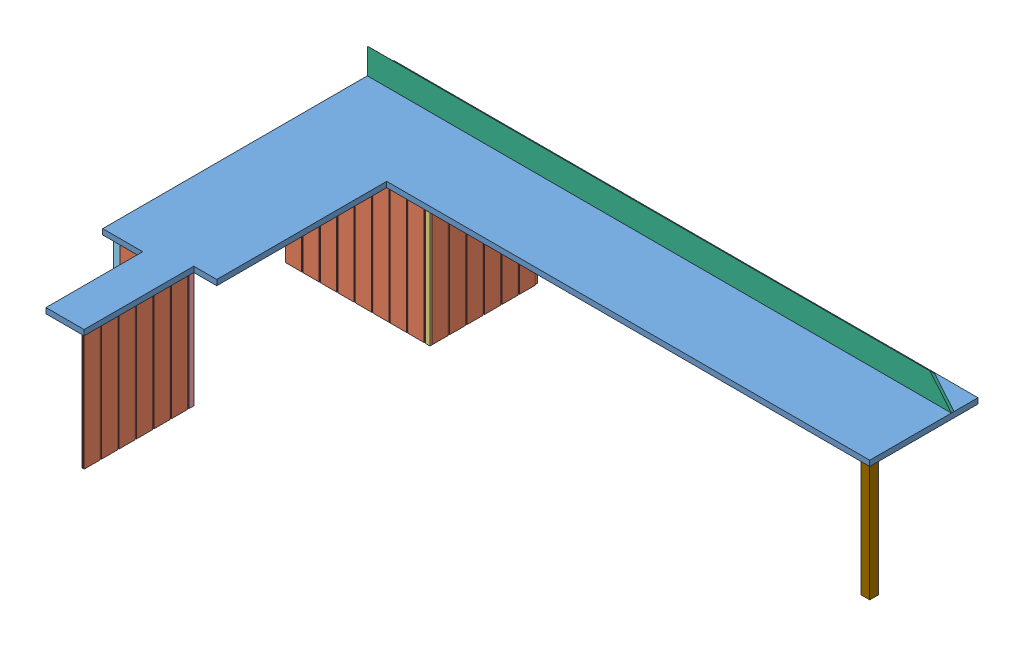
SolidWorks assembly Brüstung-Arbeit, configuration Standard. Lengths in mm.
Overall size (4046.49 1016.32 2687.4).
32 component instances, 9 part files, 94 mates.
Components (placement in the parent):
- Werkplatte-1: Werkplatte [Standard] at (-2563.2532 392.3163 2702.7833) size (4046.49 38 2687.4)
- Schalbrett-1: Schalbrett [Standard] at (-2381.7532 392.3163 3445.7833) x (1 0 0) z (0 0 -1) size (131 800 14)
- Schalbrett-2: Schalbrett [Standard] at (-2260.7532 392.3163 3445.7833) x (1 0 0) z (0 0 -1) size (131 800 14)
- Schalbrett-3: Schalbrett [Standard] at (-2139.7532 392.3163 3445.7833) x (1 0 0) z (0 0 -1) size (131 800 14)
- Schalbrett-4: Schalbrett [Standard] at (-2018.7532 392.3163 3445.7833) x (1 0 0) z (0 0 -1) size (131 800 14)
- Schalbrett-5: Schalbrett [Standard] at (-1897.7532 392.3163 3445.7833) x (1 0 0) z (0 0 -1) size (131 800 14)
- Schalbrett-6: Schalbrett [Standard] at (-1776.7532 392.3163 3445.7833) x (1 0 0) z (0 0 -1) size (131 800 14)
- Schalbrett-7: Schalbrett [Standard] at (-1655.7532 392.3163 3445.7833) x (1 0 0) z (0 0 -1) size (131 800 14)
- Schalbrett-15: Schalbrett [Standard] at (-2502.7532 392.3163 3445.7833) x (1 0 0) z (0 0 -1) size (131 800 14)
- Schalbrett-Ecke1-1: Schalbrett-Ecke1 [Standard] at (-1534.7532 392.3163 3445.7833) x (1 0 0) z (0 0 -1) size (32 800 14)
- Schalbrett-9: Schalbrett [Standard] at (-1570.2532 392.3163 3378.2833) x (0 0 -1) z (-1 0 0) size (131 800 14)
- Schalbrett-10: Schalbrett [Standard] at (-1570.2532 392.3163 3257.2833) x (0 0 -1) z (-1 0 0) size (131 800 14)
- Schalbrett-11: Schalbrett [Standard] at (-1570.2532 392.3163 3136.2833) x (0 0 -1) z (-1 0 0) size (131 800 14)
- Schalbrett-12: Schalbrett [Standard] at (-1570.2532 392.3163 3015.2833) x (0 0 -1) z (-1 0 0) size (131 800 14)
- Schalbrett-13: Schalbrett [Standard] at (-1570.2532 392.3163 2894.2833) x (0 0 -1) z (-1 0 0) size (131 800 14)
- Schalbrett-14: Schalbrett [Standard] at (-1570.2532 392.3163 2773.2833) x (0 0 -1) z (-1 0 0) size (131 800 14)
- Schalbrett-16: Schalbrett [Standard] at (-2029.2532 392.3163 5329.6883) x (0 0 -1) z (-1 0 0) size (131 800 14)
- Schalbrett-17: Schalbrett [Standard] at (-2029.2532 392.3163 5208.6883) x (0 0 -1) z (-1 0 0) size (131 800 14)
- Schalbrett-18: Schalbrett [Standard] at (-2029.2532 392.3163 5087.6883) x (0 0 -1) z (-1 0 0) size (131 800 14)
- Schalbrett-19: Schalbrett [Standard] at (-2029.2532 392.3163 4966.6883) x (0 0 -1) z (-1 0 0) size (131 800 14)
- Schalbrett-20: Schalbrett [Standard] at (-2029.2532 392.3163 4845.6883) x (0 0 -1) z (-1 0 0) size (131 800 14)
- Schalbrett-21: Schalbrett [Standard] at (-2029.2532 392.3163 4724.6883) x (0 0 -1) z (-1 0 0) size (131 800 14)
- Schalbrett-23: Schalbrett [Standard] at (-2096.7532 392.3163 4637.1883) x (-1 0 0) z (0 0 1) size (131 800 14)
- Schalbrett-24: Schalbrett [Standard] at (-2217.7532 392.3163 4637.1883) x (-1 0 0) z (0 0 1) size (131 800 14)
- Schalbrett-25: Schalbrett [Standard] at (-2338.7532 392.3163 4637.1883) x (-1 0 0) z (0 0 1) size (131 800 14)
- Schalbrett-26: Schalbrett [Standard] at (-2459.7532 392.3163 4637.1883) x (-1 0 0) z (0 0 1) size (131 800 14)
- Schalbrett-Ecke2-1: Schalbrett-Ecke2 [Standard] at (-2029.2532 392.3163 4603.6883) x (0 0 -1) z (-1 0 0) size (34 800 14)
- Schalbrett-Ecke3-1: Schalbrett-Ecke3 [Standard] at (-2580.7532 392.3163 4637.1883) x (-1 0 0) z (0 0 1) size (43 800 14)
- Steckdosenleiste-1: Steckdosenleiste [Standard] at (-540.0103 519.4748 2868.9113) size (4046.49 178.32 18)
- Tunnel-Unten-1: Tunnel-Unten [Standard] at (-2488.2532 242.3163 4041.4883) x (0 0 -1) z (1 0 0) size (1177.4 18 150)
- Tunnel-Vorn-1: Tunnel-Vorn [Standard] at (-2431.2532 326.3163 4041.4883) x (0 0 -1) z (1 0 0) size (1177.4 132 18)
- Bein-1: Bein [Standard] at (1453.2326 -407.6837 3422.7833) size (60 800 60)
Mates (geometry in assembly coordinates):
- Deckungsgleich1: coincident anti-aligned: plane of Werkplatte-1 through (-2563.2532 392.3163 2702.7833) normal (0 -1 0); plane of Schalbrett-15 through (-2453.2532 392.3163 3448.7833) normal (0 1 0)
- Deckungsgleich2: coincident anti-aligned: plane of Werkplatte-1 through (-2563.2532 392.3163 2702.7833) normal (0 -1 0); plane of Schalbrett-1 through (-2332.2532 392.3163 3448.7833) normal (0 1 0)
- Deckungsgleich3: coincident anti-aligned: plane of Werkplatte-1 through (-2563.2532 392.3163 2702.7833) normal (0 -1 0); plane of Schalbrett-2 through (-2211.2532 392.3163 3448.7833) normal (0 1 0)
- Deckungsgleich4: coincident anti-aligned: plane of Werkplatte-1 through (-2563.2532 392.3163 2702.7833) normal (0 -1 0); plane of Schalbrett-3 through (-2090.2532 392.3163 3448.7833) normal (0 1 0)
- Deckungsgleich5: coincident anti-aligned: plane of Werkplatte-1 through (-2563.2532 392.3163 2702.7833) normal (0 -1 0); plane of Schalbrett-4 through (-1969.2532 392.3163 3448.7833) normal (0 1 0)
- Deckungsgleich6: coincident anti-aligned: plane of Werkplatte-1 through (-2563.2532 392.3163 2702.7833) normal (0 -1 0); plane of Schalbrett-5 through (-1848.2532 392.3163 3448.7833) normal (0 1 0)
- Deckungsgleich7: coincident anti-aligned: plane of Werkplatte-1 through (-2563.2532 392.3163 2702.7833) normal (0 -1 0); plane of Schalbrett-6 through (-1727.2532 392.3163 3448.7833) normal (0 1 0)
- Deckungsgleich8: coincident anti-aligned: plane of Werkplatte-1 through (-2563.2532 392.3163 2702.7833) normal (0 -1 0); plane of Schalbrett-7 through (-1606.2532 392.3163 3448.7833) normal (0 1 0)
- Deckungsgleich10: coincident aligned: plane of Werkplatte-1 through (-2563.2532 430.3163 4630.1883) normal (-1 0 0); plane of Schalbrett-15 through (-2563.2532 -407.6837 3447.7833) normal (-1 0 0)
- Deckungsgleich11: coincident anti-aligned: plane of Schalbrett-1 through (-2432.2532 -407.6837 3447.7833) normal (0 0 -1); plane of Schalbrett-15 through (-2442.2532 -407.6837 3447.7833) normal (0 0 1)
- Deckungsgleich12: coincident anti-aligned: plane of Schalbrett-1 through (-2321.2532 -407.6837 3447.7833) normal (0 0 1); plane of Schalbrett-2 through (-2311.2532 -407.6837 3447.7833) normal (0 0 -1)
- Deckungsgleich13: coincident anti-aligned: plane of Schalbrett-2 through (-2200.2532 -407.6837 3447.7833) normal (0 0 1); plane of Schalbrett-3 through (-2190.2532 -407.6837 3447.7833) normal (0 0 -1)
- Deckungsgleich14: coincident anti-aligned: plane of Schalbrett-3 through (-2079.2532 -407.6837 3447.7833) normal (0 0 1); plane of Schalbrett-4 through (-2069.2532 -407.6837 3447.7833) normal (0 0 -1)
- Deckungsgleich15: coincident anti-aligned: plane of Schalbrett-4 through (-1958.2532 -407.6837 3447.7833) normal (0 0 1); plane of Schalbrett-5 through (-1948.2532 -407.6837 3447.7833) normal (0 0 -1)
- Deckungsgleich16: coincident anti-aligned: plane of Schalbrett-5 through (-1837.2532 -407.6837 3447.7833) normal (0 0 1); plane of Schalbrett-6 through (-1827.2532 -407.6837 3447.7833) normal (0 0 -1)
- Deckungsgleich17: coincident anti-aligned: plane of Schalbrett-6 through (-1716.2532 -407.6837 3447.7833) normal (0 0 1); plane of Schalbrett-7 through (-1706.2532 -407.6837 3447.7833) normal (0 0 -1)
- Deckungsgleich19: coincident aligned: plane of Werkplatte-1 through (-1863.2532 430.3163 3452.7833) normal (0 0 1); plane of Schalbrett-15 through (-2453.2532 -407.6837 3452.7833) normal (0 0 1)
- Deckungsgleich20: coincident anti-aligned: plane of Schalbrett-1 through (-2432.2532 -407.6837 3443.7833) normal (-1 0 0); plane of Schalbrett-15 through (-2432.2532 -407.6837 3447.7833) normal (1 0 0)
- Deckungsgleich21: coincident anti-aligned: plane of Schalbrett-1 through (-2311.2532 -407.6837 3447.7833) normal (1 0 0); plane of Schalbrett-2 through (-2311.2532 -407.6837 3443.7833) normal (-1 0 0)
- Deckungsgleich22: coincident anti-aligned: plane of Schalbrett-2 through (-2190.2532 -407.6837 3447.7833) normal (1 0 0); plane of Schalbrett-3 through (-2190.2532 -407.6837 3443.7833) normal (-1 0 0)
- Deckungsgleich23: coincident anti-aligned: plane of Schalbrett-3 through (-2069.2532 -407.6837 3447.7833) normal (1 0 0); plane of Schalbrett-4 through (-2069.2532 -407.6837 3443.7833) normal (-1 0 0)
- Deckungsgleich24: coincident anti-aligned: plane of Schalbrett-4 through (-1948.2532 -407.6837 3447.7833) normal (1 0 0); plane of Schalbrett-5 through (-1948.2532 -407.6837 3443.7833) normal (-1 0 0)
- Deckungsgleich25: coincident anti-aligned: plane of Schalbrett-5 through (-1827.2532 -407.6837 3447.7833) normal (1 0 0); plane of Schalbrett-6 through (-1827.2532 -407.6837 3443.7833) normal (-1 0 0)
- Deckungsgleich26: coincident anti-aligned: plane of Schalbrett-6 through (-1706.2532 -407.6837 3447.7833) normal (1 0 0); plane of Schalbrett-7 through (-1706.2532 -407.6837 3443.7833) normal (-1 0 0)
- Deckungsgleich28: coincident anti-aligned: plane of Werkplatte-1 through (-2563.2532 392.3163 2702.7833) normal (0 -1 0); plane of Schalbrett-Ecke1-1 through (-1485.2532 392.3163 3448.7833) normal (0 1 0)
- Deckungsgleich29: coincident anti-aligned: plane of Schalbrett-7 through (-1595.2532 -407.6837 3447.7833) normal (0 0 1); plane of Schalbrett-Ecke1-1 through (-1585.2532 -407.6837 3447.7833) normal (0 0 -1)
- Deckungsgleich30: coincident anti-aligned: plane of Schalbrett-7 through (-1585.2532 -407.6837 3447.7833) normal (1 0 0); plane of Schalbrett-Ecke1-1 through (-1585.2532 -407.6837 3443.7833) normal (-1 0 0)
- Deckungsgleich31: coincident anti-aligned: plane of Werkplatte-1 through (-2563.2532 392.3163 2702.7833) normal (0 -1 0); plane of Schalbrett-9 through (-1567.2532 392.3163 3328.7833) normal (0 1 0)
- Deckungsgleich32: coincident anti-aligned: plane of Werkplatte-1 through (-2563.2532 392.3163 2702.7833) normal (0 -1 0); plane of Schalbrett-10 through (-1567.2532 392.3163 3207.7833) normal (0 1 0)
- Deckungsgleich33: coincident anti-aligned: plane of Werkplatte-1 through (-2563.2532 392.3163 2702.7833) normal (0 -1 0); plane of Schalbrett-11 through (-1567.2532 392.3163 3086.7833) normal (0 1 0)
- Deckungsgleich34: coincident anti-aligned: plane of Werkplatte-1 through (-2563.2532 392.3163 2702.7833) normal (0 -1 0); plane of Schalbrett-12 through (-1567.2532 392.3163 2965.7833) normal (0 1 0)
- Deckungsgleich35: coincident anti-aligned: plane of Werkplatte-1 through (-2563.2532 392.3163 2702.7833) normal (0 -1 0); plane of Schalbrett-13 through (-1567.2532 392.3163 2844.7833) normal (0 1 0)
- Deckungsgleich36: coincident anti-aligned: plane of Werkplatte-1 through (-2563.2532 392.3163 2702.7833) normal (0 -1 0); plane of Schalbrett-14 through (-1567.2532 392.3163 2723.7833) normal (0 1 0)
- Deckungsgleich37: coincident anti-aligned: plane of Schalbrett-Ecke1-1 through (-1474.2532 -407.6837 3438.7833) normal (0 0 -1); plane of Schalbrett-9 through (-1568.2532 -407.6837 3438.7833) normal (0 0 1)
- Deckungsgleich38: coincident aligned: plane of Schalbrett-Ecke1-1 through (-1563.2532 592.3163 3438.7833) normal (1 0 0); plane of Schalbrett-9 through (-1563.2532 -407.6837 3328.7833) normal (1 0 0)
- Deckungsgleich39: coincident anti-aligned: plane of Schalbrett-9 through (-1568.2532 -407.6837 3317.7833) normal (1 0 0); plane of Schalbrett-10 through (-1568.2532 -407.6837 3307.7833) normal (-1 0 0)
- Deckungsgleich40: coincident anti-aligned: plane of Schalbrett-10 through (-1568.2532 -407.6837 3196.7833) normal (1 0 0); plane of Schalbrett-11 through (-1568.2532 -407.6837 3186.7833) normal (-1 0 0)
- Deckungsgleich41: coincident anti-aligned: plane of Schalbrett-11 through (-1568.2532 -407.6837 3075.7833) normal (1 0 0); plane of Schalbrett-12 through (-1568.2532 -407.6837 3065.7833) normal (-1 0 0)
- Deckungsgleich42: coincident anti-aligned: plane of Schalbrett-12 through (-1568.2532 -407.6837 2954.7833) normal (1 0 0); plane of Schalbrett-13 through (-1568.2532 -407.6837 2944.7833) normal (-1 0 0)
- Deckungsgleich43: coincident anti-aligned: plane of Schalbrett-13 through (-1568.2532 -407.6837 2833.7833) normal (1 0 0); plane of Schalbrett-14 through (-1568.2532 -407.6837 2823.7833) normal (-1 0 0)
- Deckungsgleich44: coincident anti-aligned: plane of Schalbrett-9 through (-1568.2532 -407.6837 3307.7833) normal (0 0 -1); plane of Schalbrett-10 through (-1572.2532 -407.6837 3307.7833) normal (0 0 1)
- Deckungsgleich45: coincident anti-aligned: plane of Schalbrett-10 through (-1568.2532 -407.6837 3186.7833) normal (0 0 -1); plane of Schalbrett-11 through (-1572.2532 -407.6837 3186.7833) normal (0 0 1)
- Deckungsgleich46: coincident anti-aligned: plane of Schalbrett-11 through (-1568.2532 -407.6837 3065.7833) normal (0 0 -1); plane of Schalbrett-12 through (-1572.2532 -407.6837 3065.7833) normal (0 0 1)
- Deckungsgleich47: coincident anti-aligned: plane of Schalbrett-12 through (-1568.2532 -407.6837 2944.7833) normal (0 0 -1); plane of Schalbrett-13 through (-1572.2532 -407.6837 2944.7833) normal (0 0 1)
- Deckungsgleich48: coincident anti-aligned: plane of Schalbrett-13 through (-1568.2532 -407.6837 2823.7833) normal (0 0 -1); plane of Schalbrett-14 through (-1572.2532 -407.6837 2823.7833) normal (0 0 1)
- Deckungsgleich49: coincident anti-aligned: plane of Werkplatte-1 through (-2563.2532 392.3163 2702.7833) normal (0 -1 0); plane of Schalbrett-16 through (-2026.2532 392.3163 5280.1883) normal (0 1 0)
- Deckungsgleich50: coincident anti-aligned: plane of Werkplatte-1 through (-2563.2532 392.3163 2702.7833) normal (0 -1 0); plane of Schalbrett-17 through (-2026.2532 392.3163 5159.1883) normal (0 1 0)
- Deckungsgleich51: coincident anti-aligned: plane of Werkplatte-1 through (-2563.2532 392.3163 2702.7833) normal (0 -1 0); plane of Schalbrett-18 through (-2026.2532 392.3163 5038.1883) normal (0 1 0)
- Deckungsgleich52: coincident anti-aligned: plane of Werkplatte-1 through (-2563.2532 392.3163 2702.7833) normal (0 -1 0); plane of Schalbrett-19 through (-2026.2532 392.3163 4917.1883) normal (0 1 0)
- Deckungsgleich53: coincident anti-aligned: plane of Werkplatte-1 through (-2563.2532 392.3163 2702.7833) normal (0 -1 0); plane of Schalbrett-20 through (-2026.2532 392.3163 4796.1883) normal (0 1 0)
- Deckungsgleich54: coincident anti-aligned: plane of Werkplatte-1 through (-2563.2532 392.3163 2702.7833) normal (0 -1 0); plane of Schalbrett-21 through (-2026.2532 392.3163 4675.1883) normal (0 1 0)
- Deckungsgleich56: coincident anti-aligned: plane of Werkplatte-1 through (-2563.2532 392.3163 2702.7833) normal (0 -1 0); plane of Schalbrett-23 through (-2146.2532 392.3163 4634.1883) normal (0 1 0)
- Deckungsgleich57: coincident anti-aligned: plane of Werkplatte-1 through (-2563.2532 392.3163 2702.7833) normal (0 -1 0); plane of Schalbrett-24 through (-2267.2532 392.3163 4634.1883) normal (0 1 0)
- Deckungsgleich58: coincident anti-aligned: plane of Werkplatte-1 through (-2563.2532 392.3163 2702.7833) normal (0 -1 0); plane of Schalbrett-25 through (-2388.2532 392.3163 4634.1883) normal (0 1 0)
- Deckungsgleich59: coincident anti-aligned: plane of Werkplatte-1 through (-2563.2532 392.3163 2702.7833) normal (0 -1 0); plane of Schalbrett-26 through (-2509.2532 392.3163 4634.1883) normal (0 1 0)
- Deckungsgleich61: coincident aligned: plane of Werkplatte-1 through (-2022.2532 430.3163 5390.1883) normal (0 0 1); plane of Schalbrett-16 through (-2027.2532 -407.6837 5390.1883) normal (0 0 1)
- Deckungsgleich62: coincident aligned: plane of Werkplatte-1 through (-2022.2532 430.3163 5390.1883) normal (1 0 0); plane of Schalbrett-16 through (-2022.2532 -407.6837 5280.1883) normal (1 0 0)
- Deckungsgleich63: coincident anti-aligned: plane of Schalbrett-16 through (-2027.2532 -407.6837 5269.1883) normal (1 0 0); plane of Schalbrett-17 through (-2027.2532 -407.6837 5259.1883) normal (-1 0 0)
- Deckungsgleich64: coincident anti-aligned: plane of Schalbrett-17 through (-2027.2532 -407.6837 5148.1883) normal (1 0 0); plane of Schalbrett-18 through (-2027.2532 -407.6837 5138.1883) normal (-1 0 0)
- Deckungsgleich65: coincident anti-aligned: plane of Schalbrett-18 through (-2027.2532 -407.6837 5027.1883) normal (1 0 0); plane of Schalbrett-19 through (-2027.2532 -407.6837 5017.1883) normal (-1 0 0)
- Deckungsgleich66: coincident anti-aligned: plane of Schalbrett-19 through (-2027.2532 -407.6837 4906.1883) normal (1 0 0); plane of Schalbrett-20 through (-2027.2532 -407.6837 4896.1883) normal (-1 0 0)
- Deckungsgleich67: coincident anti-aligned: plane of Schalbrett-20 through (-2027.2532 -407.6837 4785.1883) normal (1 0 0); plane of Schalbrett-21 through (-2027.2532 -407.6837 4775.1883) normal (-1 0 0)
- Deckungsgleich69: coincident anti-aligned: plane of Schalbrett-16 through (-2027.2532 -407.6837 5259.1883) normal (0 0 -1); plane of Schalbrett-17 through (-2031.2532 -407.6837 5259.1883) normal (0 0 1)
- Deckungsgleich70: coincident anti-aligned: plane of Schalbrett-17 through (-2027.2532 -407.6837 5138.1883) normal (0 0 -1); plane of Schalbrett-18 through (-2031.2532 -407.6837 5138.1883) normal (0 0 1)
- Deckungsgleich71: coincident anti-aligned: plane of Schalbrett-18 through (-2027.2532 -407.6837 5017.1883) normal (0 0 -1); plane of Schalbrett-19 through (-2031.2532 -407.6837 5017.1883) normal (0 0 1)
- Deckungsgleich72: coincident anti-aligned: plane of Schalbrett-19 through (-2027.2532 -407.6837 4896.1883) normal (0 0 -1); plane of Schalbrett-20 through (-2031.2532 -407.6837 4896.1883) normal (0 0 1)
- Deckungsgleich73: coincident anti-aligned: plane of Schalbrett-20 through (-2027.2532 -407.6837 4775.1883) normal (0 0 -1); plane of Schalbrett-21 through (-2031.2532 -407.6837 4775.1883) normal (0 0 1)
- Deckungsgleich75: coincident anti-aligned: plane of Werkplatte-1 through (-2563.2532 392.3163 2702.7833) normal (0 -1 0); plane of Schalbrett-Ecke2-1 through (-2026.2532 392.3163 4554.1883) normal (0 1 0)
- Deckungsgleich76: coincident anti-aligned: plane of Schalbrett-21 through (-2027.2532 -407.6837 4664.1883) normal (1 0 0); plane of Schalbrett-Ecke2-1 through (-2027.2532 -407.6837 4654.1883) normal (-1 0 0)
- Deckungsgleich77: coincident anti-aligned: plane of Schalbrett-21 through (-2027.2532 -407.6837 4654.1883) normal (0 0 -1); plane of Schalbrett-Ecke2-1 through (-2031.2532 -407.6837 4654.1883) normal (0 0 1)
- Deckungsgleich78: coincident anti-aligned: plane of Werkplatte-1 through (-2563.2532 392.3163 2702.7833) normal (0 -1 0); plane of Schalbrett-23 through (-2146.2532 392.3163 4634.1883) normal (0 1 0)
- Deckungsgleich79: coincident anti-aligned: plane of Schalbrett-23 through (-2036.2532 -407.6837 4644.1883) normal (1 0 0); plane of Schalbrett-Ecke2-1 through (-2036.2532 -407.6837 4543.1883) normal (-1 0 0)
- Deckungsgleich80: coincident aligned: plane of Schalbrett-23 through (-2146.2532 -407.6837 4630.1883) normal (0 0 -1); plane of Schalbrett-Ecke2-1 through (-2022.2532 -607.6837 4630.1883) normal (0 0 -1)
- Deckungsgleich81: coincident anti-aligned: plane of Schalbrett-23 through (-2157.2532 -407.6837 4635.1883) normal (0 0 -1); plane of Schalbrett-24 through (-2167.2532 -407.6837 4635.1883) normal (0 0 1)
- Deckungsgleich82: coincident anti-aligned: plane of Schalbrett-23 through (-2167.2532 -407.6837 4635.1883) normal (-1 0 0); plane of Schalbrett-24 through (-2167.2532 -407.6837 4639.1883) normal (1 0 0)
- Deckungsgleich83: coincident anti-aligned: plane of Schalbrett-24 through (-2278.2532 -407.6837 4635.1883) normal (0 0 -1); plane of Schalbrett-25 through (-2288.2532 -407.6837 4635.1883) normal (0 0 1)
- Deckungsgleich85: coincident anti-aligned: plane of Schalbrett-24 through (-2288.2532 -407.6837 4635.1883) normal (-1 0 0); plane of Schalbrett-25 through (-2288.2532 -407.6837 4639.1883) normal (1 0 0)
- Deckungsgleich86: coincident anti-aligned: plane of Schalbrett-25 through (-2409.2532 -407.6837 4635.1883) normal (-1 0 0); plane of Schalbrett-26 through (-2409.2532 -407.6837 4639.1883) normal (1 0 0)
- Deckungsgleich87: coincident anti-aligned: plane of Schalbrett-25 through (-2399.2532 -407.6837 4635.1883) normal (0 0 -1); plane of Schalbrett-26 through (-2409.2532 -407.6837 4635.1883) normal (0 0 1)
- Deckungsgleich93: coincident anti-aligned: plane of Schalbrett-26 through (-2530.2532 -407.6837 4635.1883) normal (-1 0 0); plane of Schalbrett-Ecke3-1 through (-2530.2532 -407.6837 4639.1883) normal (1 0 0)
- Deckungsgleich94: coincident anti-aligned: plane of Werkplatte-1 through (-2563.2532 392.3163 2702.7833) normal (0 -1 0); plane of Schalbrett-Ecke3-1 through (-2630.2532 392.3163 4634.1883) normal (0 1 0)
- Deckungsgleich96: coincident anti-aligned: plane of Schalbrett-26 through (-2520.2532 -407.6837 4635.1883) normal (0 0 -1); plane of Schalbrett-Ecke3-1 through (-2530.2532 -407.6837 4635.1883) normal (0 0 1)
- Deckungsgleich97: coincident anti-aligned: plane of Werkplatte-1 through (-2563.2532 430.3163 2702.7833) normal (0 1 0); plane of Steckdosenleiste-1 through (-2563.2532 430.3163 2886.9113) normal (0 -1 0)
- Deckungsgleich98: coincident aligned: plane of Werkplatte-1 through (-2563.2532 430.3163 4630.1883) normal (-1 0 0); plane of Steckdosenleiste-1 through (-2563.2532 430.3163 2886.9113) normal (-1 0 0)
- Abstand1: distance = 184.128 mm anti-aligned: plane of Werkplatte-1 through (1483.2326 430.3163 2702.7833) normal (0 0 -1); plane of Steckdosenleiste-1 through (-540.0103 519.4748 2886.9113) normal (0 0 1)
- Deckungsgleich101: coincident aligned: plane of Werkplatte-1 through (-2563.2532 430.3163 4630.1883) normal (-1 0 0); plane of Tunnel-Unten-1 through (-2563.2532 260.3163 4630.1883) normal (-1 0 0)
- Deckungsgleich102: coincident anti-aligned: plane of Schalbrett-26 through (-2509.2532 -407.6837 4630.1883) normal (0 0 -1); plane of Tunnel-Unten-1 through (-2563.2532 260.3163 4630.1883) normal (0 0 1)
- Deckungsgleich103: coincident aligned: plane of Tunnel-Unten-1 through (-2413.2532 260.3163 4630.1883) normal (1 0 0); plane of Tunnel-Vorn-1 through (-2413.2532 326.3163 4041.4883) normal (1 0 0)
- Deckungsgleich104: coincident anti-aligned: plane of Tunnel-Unten-1 through (-2488.2532 260.3163 4041.4883) normal (0 1 0); plane of Tunnel-Vorn-1 through (-2413.2532 260.3163 4630.1883) normal (0 -1 0)
- Deckungsgleich105: coincident anti-aligned: plane of Werkplatte-1 through (-2563.2532 392.3163 2702.7833) normal (0 -1 0); plane of Tunnel-Vorn-1 through (-2413.2532 392.3163 4630.1883) normal (0 1 0)
- Deckungsgleich108: coincident aligned: plane of Tunnel-Unten-1 through (-2563.2532 260.3163 4630.1883) normal (0 0 1); plane of Tunnel-Vorn-1 through (-2413.2532 260.3163 4630.1883) normal (0 0 1)
- Deckungsgleich109: coincident anti-aligned: plane of Werkplatte-1 through (-2563.2532 392.3163 2702.7833) normal (0 -1 0); plane of Bein-1 through (1453.2326 392.3163 3422.7833) normal (0 1 0)
- Deckungsgleich110: coincident aligned: plane of Werkplatte-1 through (1483.2326 430.3163 3452.7833) normal (1 0 0); plane of Bein-1 through (1483.2326 392.3163 3452.7833) normal (1 0 0)
- Deckungsgleich111: coincident aligned: plane of Werkplatte-1 through (-1863.2532 430.3163 3452.7833) normal (0 0 1); plane of Bein-1 through (1423.2326 392.3163 3452.7833) normal (0 0 1)
